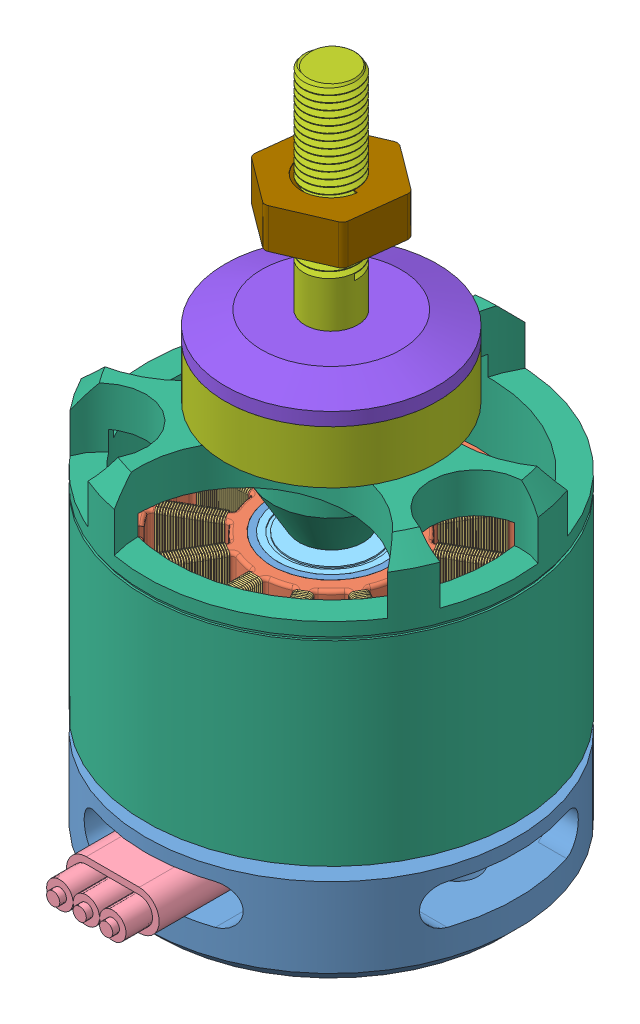
SolidWorks assembly SunnySky X2212_13_980kV, configuration Default. Lengths in mm.
Overall size (39.19 52.5 39.19).
21 component instances, 9 part files, 25 mates.
Components (placement in the parent):
- Housing_Bottom-1: Housing_Bottom [Default] at origin size (28 20 28)
- Stator-1: Stator [Default] at (0 8 0) size (22 12.2 22)
  - Stator_Steelcore-1: Stator_Steelcore [Default] at origin size (22 12.05 22)
  - Stator_Coil-1: Stator_Coil [Default] at (-2.8504 6 4.9371) x (0.5 0 -0.866025) z (0.866025 0 0.5) size (4.11 12.2 1.21)
  - Stator_Coil-2: Stator_Coil [Default] at (0 6 5.7009) x (0 0 -1) z (1 0 0) size (4.11 12.2 1.21)
  - Stator_Coil-3: Stator_Coil [Default] at (2.8504 6 4.9371) x (-0.5 0 -0.866025) z (0.866025 0 -0.5) size (4.11 12.2 1.21)
  - Stator_Coil-4: Stator_Coil [Default] at (4.9371 6 2.8504) x (-0.866025 0 -0.5) z (0.5 0 -0.866025) size (4.11 12.2 1.21)
  - Stator_Coil-5: Stator_Coil [Default] at (5.7009 6 0) x (-1 0 0) z (0 0 -1) size (4.11 12.2 1.21)
  - Stator_Coil-6: Stator_Coil [Default] at (4.9371 6 -2.8504) x (-0.866025 0 0.5) z (-0.5 0 -0.866025) size (4.11 12.2 1.21)
  - Stator_Coil-7: Stator_Coil [Default] at (2.8504 6 -4.9371) x (-0.5 0 0.866025) z (-0.866025 0 -0.5) size (4.11 12.2 1.21)
  - Stator_Coil-8: Stator_Coil [Default] at (0 6 -5.7009) x (0 0 1) z (-1 0 0) size (4.11 12.2 1.21)
  - Stator_Coil-9: Stator_Coil [Default] at (-2.8504 6 -4.9371) x (0.5 0 0.866025) z (-0.866025 0 0.5) size (4.11 12.2 1.21)
  - Stator_Coil-10: Stator_Coil [Default] at (-4.9371 6 -2.8504) x (0.866025 0 0.5) z (-0.5 0 0.866025) size (4.11 12.2 1.21)
  - Stator_Coil-11: Stator_Coil [Default] at (-5.7009 6 0) size (4.11 12.2 1.21)
  - Stator_Coil-12: Stator_Coil [Default] at (-4.9371 6 2.8504) x (0.866025 0 -0.5) z (0.5 0 0.866025) size (4.11 12.2 1.21)
- Wiring-1: Wiring [Default] at (0.0116 4.5 16.5) x (1 0 0) z (0 0 -1) size (7 3 14.5)
- Rotor-1: Rotor [Default] x (-0.598049 0 0.80146) z (-0.80146 0 -0.598049) size (8 31.7 8)
- Housing_Upper-1: Housing_Upper [Default] at (0 8 0) x (-0.598049 0 0.80146) z (-0.80146 0 -0.598049) size (28 22 28)
- CapScrew-1: CapScrew [Default] at (0 28.5 0) x (0.117196 0 -0.993109) z (0.993109 0 0.117196) size (16 22.3 16)
- Cap-1: Cap [Default] at (0 32.5 0) x (0.117196 0 -0.993109) z (0.993109 0 0.117196) size (16 2 16)
- Nut-1: Nut [Default] at (0 40.4 0) x (0.117196 0 -0.993109) z (0.993109 0 0.117196) size (9.08 3.45 8)
Mates (geometry in assembly coordinates):
- Concentric1: concentric aligned: cylinder of Stator-1/Stator_Steelcore-1 through (0 20 0) axis (0 -1 0) radius 4.5; cylinder of Housing_Bottom-1 through (0 20 0) axis (0 -1 0) radius 4.5
- Coincident1: coincident aligned: plane of Housing_Bottom-1 through (0 20 0) normal (0 1 0); plane of Stator-1/Stator_Steelcore-1 through (0 20 0) normal (0 1 0)
- Coincident2: coincident anti-aligned: plane of Housing_Bottom-1 through (0 3 0) normal (0 1 0); plane of Wiring-1 through (-1.9884 3 6.5) normal (0 -1 0)
- Lock1: lock: unknown of Housing_Bottom-1; unknown of Wiring-1
- Tangent1: tangent anti-aligned: cylinder of Housing_Bottom-1 through (0 20 0) axis (0 -1 0) radius 4.5; plane of Wiring-1 through (0.0116 4.5 4.5) normal (0 0 -1)
- Coincident6: coincident aligned: plane of Housing_Bottom-1 through (0 20 0) normal (0 1 0); plane of Rotor-1 through (0 20 0) normal (0 1 0)
- Concentric2: concentric aligned: cylinder of Housing_Bottom-1 through (0 14.3137 0) axis (0 -1 0) radius 4; cylinder of Rotor-1 through (0 20 0) axis (0 -1 0) radius 4
- Concentric3: concentric anti-aligned: cylinder of Rotor-1 through (0 30 0) axis (0 -1 0) radius 1.5; cylinder of Housing_Upper-1 through (0 8 0) axis (0 1 0) radius 1.5
- Distance1: distance = 8 mm aligned: plane of Housing_Upper-1 through (0 8 0) normal (0 1 0); plane of Housing_Bottom-1 through (0 0 0) normal (0 1 0)
- Coincident10: coincident aligned: plane of Housing_Bottom-1 through (0 0 0) normal (0 0 1); plane of Stator-1 through (0 8 0) normal (0 0 1)
- Coincident11: coincident aligned: plane of Rotor-1 through (0 0 0) normal (-0.80146 0 -0.598049); plane of Housing_Upper-1 through (0 8 0) normal (-0.80146 0 -0.598049)
- Coincident12: coincident aligned: plane of Housing_Bottom-1 through (0 0 0) normal (0 0 1); plane of assembly through (0 0 0) normal (0 0 1)
- Coincident13: coincident aligned: plane of Housing_Bottom-1 through (0 0 0) normal (0 1 0); plane of assembly through (0 0 0) normal (0 1 0)
- Coincident14: coincident aligned: plane of Housing_Bottom-1 through (0 0 0) normal (1 0 0); plane of assembly through (0 0 0) normal (1 0 0)
- Concentric4: concentric anti-aligned: cylinder of Housing_Upper-1 through (0 9.9135 0) axis (0 1 0) radius 4.45; cylinder of CapScrew-1 through (0 30 0) axis (0 -1 0) radius 4.5
- Concentric5: concentric aligned: cylinder of Housing_Upper-1 through (-2.3704 28.5 -5.5119) axis (0 1 0) radius 0.625; cylinder of CapScrew-1 through (-2.3704 32.5 -5.5119) axis (0 1 0) radius 0.85
- Concentric6: concentric aligned: cylinder of Housing_Upper-1 through (5.9587 28.5 0.7032) axis (0 1 0) radius 0.625; cylinder of CapScrew-1 through (5.9587 32.5 0.7032) axis (0 1 0) radius 0.85
- Concentric7: concentric aligned: cylinder of Housing_Upper-1 through (-3.5883 28.5 4.8088) axis (0 1 0) radius 0.625; cylinder of CapScrew-1 through (-3.5883 32.5 4.8088) axis (0 1 0) radius 0.85
- Coincident15: coincident anti-aligned: plane of Housing_Upper-1 through (0 28.5 0) normal (0 1 0); plane of CapScrew-1 through (0 28.5 0) normal (0 -1 0)
- Concentric8: concentric anti-aligned: cylinder of CapScrew-1 through (0 50.5 0) axis (0 -1 0) radius 2; cylinder of Cap-1 through (0 32.5 0) axis (0 1 0) radius 2
- Coincident16: coincident anti-aligned: plane of CapScrew-1 through (0 32.5 0) normal (0 1 0); plane of Cap-1 through (0 32.5 0) normal (0 -1 0)
- Coincident19: coincident aligned: plane of CapScrew-1 through (0 28.5 0) normal (0.993109 0 0.117196); plane of Cap-1 through (0 32.5 0) normal (0.993109 0 0.117196)
- Concentric22: concentric anti-aligned: cylinder of CapScrew-1 through (0 50.5 0) axis (0 -1 0) radius 2; cylinder of Nut-1 through (0 40.4 0) axis (0 1 0) radius 2.25
- Parallel3: parallel aligned: plane of Cap-1 through (0 34.5 0) normal (0 1 0); plane of Nut-1 through (0 43.4 0) normal (0 1 0)
- Coincident26: coincident aligned: plane of Cap-1 through (0 32.5 0) normal (0.993109 0 0.117196); plane of Nut-1 through (0 40.4 0) normal (0.993109 0 0.117196)
